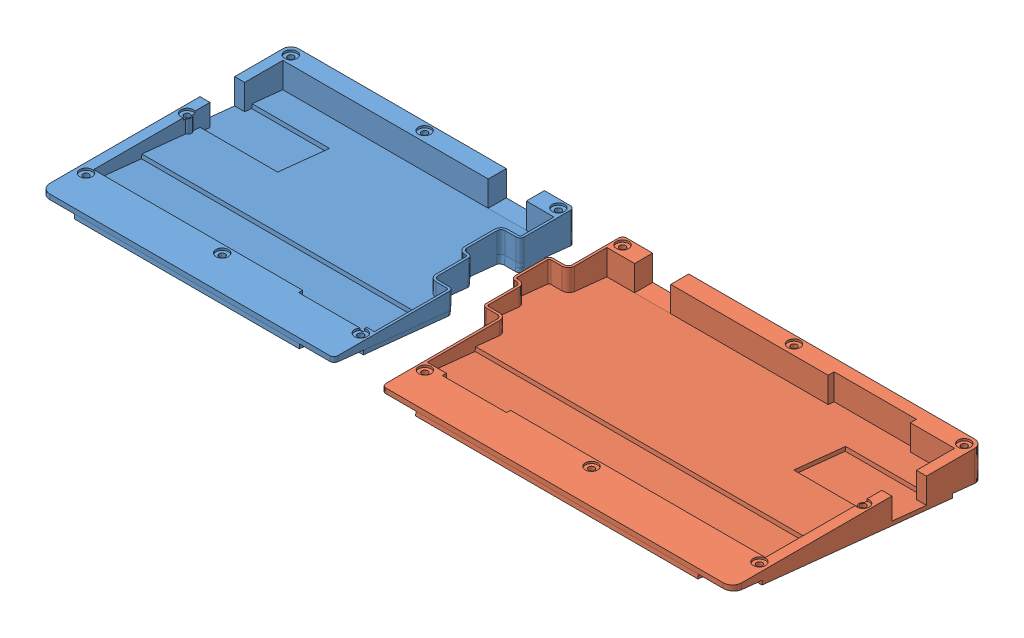
SolidWorks assembly fit_check, configuration Default. Lengths in mm.
Overall size (344.74 18.38 124.89).
2 component instances, 2 part files, 2 mates.
Components (placement in the parent):
- left-6: left [Default] at (26.708 138.4751 57.6625) size (146.11 17.58 124.89)
- right-6: right [Default] at (147.4415 143.1751 29.7893) size (188.97 18.38 124.89)
Mates (geometry in assembly coordinates):
- Coincident1: coincident: line of left-6 through (96.7666 139.8862 122.7135) axis (-1 0 0); plane of right-6 through (108.7201 143.1751 122.7135) normal (0 0 1)
- Coincident3: coincident aligned: plane of left-6 through (193.7494 129.7282 7.0375) normal (0 0.994522 -0.104528); plane of right-6 through (14.6211 139.6342 101.2875) normal (0 0.994522 -0.104528)
